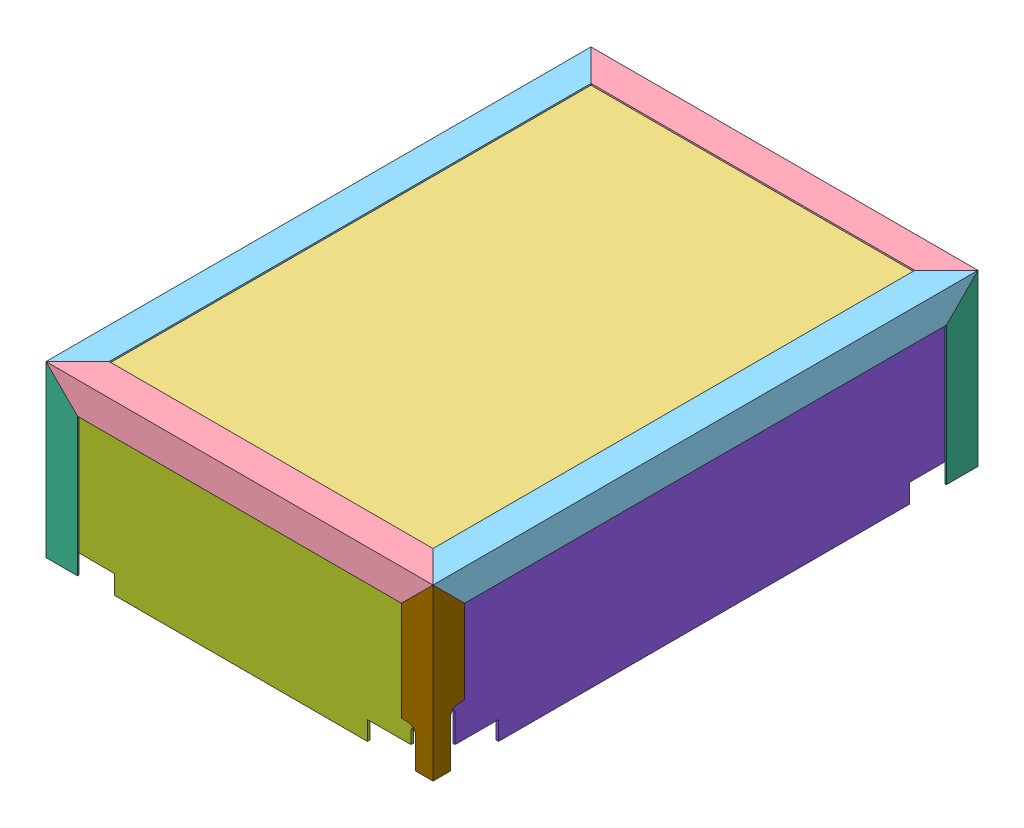
SolidWorks assembly couvercle, configuration Défaut. Lengths in mm.
Overall size (490 215 690).
13 component instances, 9 part files, 32 mates.
Components (placement in the parent):
- plaque_acrylique_680x210-2: plaque_acrylique_680x210 [Défaut] at (-694.8689 73.91 -173.3892) x (0 0 -1) z (1 0 0) size (680 210 3)
- plaque_acrylique_380x210-2: plaque_acrylique_380x210 [Défaut] at (-401.8689 73.91 -516.3892) size (480 210 3)
- plaque_acrylique_380x680-1: plaque_acrylique_380x680 [Défaut] at (-401.8689 178.91 -173.3892) x (1 0 0) z (0 1 0) size (480 680 3)
- eclisse_40x40x404_bisote_x2-1: eclisse_40x40x404_bisote_x2 [Défaut] at (-206.8689 163.7964 -498.3892) x (0 0 1) z (0 -1 0) size (40 490 40)
- eclisse_40x40x704_bisote_x2-1: eclisse_40x40x704_bisote_x2 [Défaut] at (-226.9825 163.91 -518.3892) x (0 -1 0) z (-1 0 0) size (40 690 40)
- eclisse_40x40x404_bisote_x2-2: eclisse_40x40x404_bisote_x2 [Défaut] at (-696.8689 163.7964 151.6108) x (0 0 -1) z (0 -1 0) size (40 490 40)
- eclisse_40x40x704_bisote_x2-2: eclisse_40x40x704_bisote_x2 [Défaut] at (-676.8689 163.7964 -518.3892) x (1 0 0) z (0 -1 0) size (40 690 40)
- eclisse_40x40x222_bisote_x1-1: eclisse_40x40x222_bisote_x1 [Défaut] at (-676.7552 183.91 -498.3892) x (0 0 1) z (1 0 0) size (40 213 40)
- eclisse_40x40x222_bisote_x1-2: eclisse_40x40x222_bisote_x1 [Défaut] at (-226.8689 183.91 -498.2755) x (-1 0 0) z (0 0 1) size (40 213 40)
- eclisse_40x40x222_bisote_x1-4: eclisse_40x40x222_bisote_x1 [Défaut] at (-676.8689 183.91 151.4972) x (1 0 0) z (0 0 -1) size (40 213 40)
- plaque_acrylique_380x210_Moteur-1: plaque_acrylique_380x210_Moteur [Défaut] at (-401.8689 73.91 166.6108) size (480 210 3)
- plaque_acrylique_680x210_moteur-1: plaque_acrylique_680x210_moteur [Défaut] at (-211.8689 73.91 -173.3892) x (0 0 -1) z (1 0 0) size (680 210 3)
- eclisse_40x40x222_bisote_x1_Moteur-1: eclisse_40x40x222_bisote_x1_Moteur [Défaut] at (-226.9825 183.91 151.6108) x (0 0 -1) z (-1 0 0) size (40 213 40)
Mates (geometry in assembly coordinates):
- Coïncidente1: coincident anti-aligned: plane of plaque_acrylique_380x680-1 through (-401.8689 181.91 -173.3892) normal (0 1 0); plane of eclisse_40x40x704_bisote_x2-1 through (-208.8689 181.91 171.6108) normal (0 -1 0)
- Coïncidente2: coincident anti-aligned: plane of eclisse_40x40x704_bisote_x2-1 through (-208.8689 181.91 171.6108) normal (-1 0 0); plane of plaque_acrylique_680x210_moteur-1 through (-208.8689 73.91 -173.3892) normal (1 0 0)
- Coïncidente3: coincident anti-aligned: plane of plaque_acrylique_380x210-2 through (-401.8689 73.91 -516.3892) normal (0 0 -1); plane of eclisse_40x40x404_bisote_x2-1 through (-696.8689 181.91 -516.3892) normal (0 0 1)
- Coïncidente4: coincident anti-aligned: plane of plaque_acrylique_380x680-1 through (-401.8689 181.91 -173.3892) normal (0 1 0); plane of eclisse_40x40x404_bisote_x2-1 through (-696.8689 181.91 -516.3892) normal (0 -1 0)
- Coïncidente5: coincident anti-aligned: plane of plaque_acrylique_680x210-2 through (-694.8689 73.91 -173.3892) normal (-1 0 0); plane of eclisse_40x40x704_bisote_x2-2 through (-694.8689 181.91 171.6108) normal (1 0 0)
- Coïncidente6: coincident anti-aligned: plane of plaque_acrylique_380x680-1 through (-401.8689 181.91 -173.3892) normal (0 1 0); plane of eclisse_40x40x704_bisote_x2-2 through (-694.8689 181.91 171.6108) normal (0 -1 0)
- Coïncidente7: coincident anti-aligned: plane of eclisse_40x40x404_bisote_x2-2 through (-206.8689 181.91 169.6108) normal (0 0 -1); plane of plaque_acrylique_380x210_Moteur-1 through (-401.8689 73.91 169.6108) normal (0 0 1)
- Coïncidente9: coincident anti-aligned: plane of plaque_acrylique_380x210_Moteur-1 through (-401.8689 73.91 169.6108) normal (0 0 1); plane of eclisse_40x40x222_bisote_x1_Moteur-1 through (-208.8689 -31.09 169.6108) normal (0 0 -1)
- Coïncidente10: coincident anti-aligned: plane of plaque_acrylique_680x210_moteur-1 through (-208.8689 73.91 -173.3892) normal (1 0 0); plane of eclisse_40x40x222_bisote_x1_Moteur-1 through (-208.8689 -31.09 169.6108) normal (-1 0 0)
- Coïncidente11: coincident anti-aligned: plane of plaque_acrylique_380x210-2 through (-401.8689 73.91 -516.3892) normal (0 0 -1); plane of eclisse_40x40x222_bisote_x1-2 through (-208.8689 -31.09 -516.3892) normal (0 0 1)
- Coïncidente12: coincident anti-aligned: plane of eclisse_40x40x222_bisote_x1-2 through (-208.8689 -31.09 -516.3892) normal (-1 0 0); plane of plaque_acrylique_680x210_moteur-1 through (-208.8689 73.91 -173.3892) normal (1 0 0)
- Coïncidente13: coincident anti-aligned: plane of plaque_acrylique_680x210-2 through (-694.8689 73.91 -173.3892) normal (-1 0 0); plane of eclisse_40x40x222_bisote_x1-1 through (-694.8689 -31.09 -516.3892) normal (1 0 0)
- Coïncidente14: coincident anti-aligned: plane of plaque_acrylique_380x210-2 through (-401.8689 73.91 -516.3892) normal (0 0 -1); plane of eclisse_40x40x222_bisote_x1-1 through (-694.8689 -31.09 -516.3892) normal (0 0 1)
- Coïncidente15: coincident anti-aligned: plane of eclisse_40x40x222_bisote_x1-4 through (-694.8689 -31.09 169.6108) normal (0 0 -1); plane of plaque_acrylique_380x210_Moteur-1 through (-401.8689 73.91 169.6108) normal (0 0 1)
- Coïncidente16: coincident anti-aligned: plane of plaque_acrylique_680x210-2 through (-694.8689 73.91 -173.3892) normal (-1 0 0); plane of eclisse_40x40x222_bisote_x1-4 through (-694.8689 -31.09 169.6108) normal (1 0 0)
- Coïncidente19: coincident anti-aligned: line of plaque_acrylique_380x210_Moteur-1 through (-211.8689 -7.09 166.6108) axis (0 1 0); line of plaque_acrylique_680x210_moteur-1 through (-211.8689 178.91 166.6108) axis (0 -1 0)
- Coïncidente20: coincident aligned: plane of plaque_acrylique_380x210_Moteur-1 through (-211.8689 -7.09 166.6108) normal (0 -1 0); plane of plaque_acrylique_680x210_moteur-1 through (-211.8689 -7.09 166.6108) normal (0 -1 0)
- Coïncidente21: coincident aligned: line of plaque_acrylique_680x210-2 through (-691.8689 178.91 166.6108) axis (0 -1 0); line of plaque_acrylique_380x210_Moteur-1 through (-691.8689 178.91 166.6108) axis (0 -1 0)
- Coïncidente22: coincident aligned: plane of plaque_acrylique_680x210-2 through (-694.8689 -7.09 166.6108) normal (0 -1 0); plane of plaque_acrylique_380x210_Moteur-1 through (-691.8689 -7.09 166.6108) normal (0 -1 0)
- Coïncidente23: coincident anti-aligned: line of plaque_acrylique_680x210-2 through (-691.8689 -7.09 -513.3892) axis (0 1 0); line of plaque_acrylique_380x210-2 through (-691.8689 178.91 -513.3892) axis (0 -1 0)
- Coïncidente24: coincident aligned: plane of plaque_acrylique_680x210-2 through (-694.8689 -7.09 -513.3892) normal (0 -1 0); plane of plaque_acrylique_380x210-2 through (-691.8689 -7.09 -516.3892) normal (0 -1 0)
- Coïncidente28: coincident anti-aligned: line of plaque_acrylique_380x680-1 through (-691.8689 178.91 166.6108) axis (1 0 0); line of plaque_acrylique_380x210_Moteur-1 through (-211.8689 178.91 166.6108) axis (-1 0 0)
- Coïncidente29: coincident aligned: line of plaque_acrylique_680x210-2 through (-691.8689 178.91 -513.3892) axis (0 0 1); line of plaque_acrylique_380x680-1 through (-691.8689 178.91 -513.3892) axis (0 0 1)
- Coïncidente30: coincident anti-aligned: plane of plaque_acrylique_380x680-1 through (-401.8689 181.91 -173.3892) normal (0 1 0); plane of eclisse_40x40x404_bisote_x2-2 through (-206.8689 181.91 169.6108) normal (0 -1 0)
- Coïncidente31: coincident anti-aligned: line of eclisse_40x40x404_bisote_x2-2 through (-206.8689 183.91 171.6108) axis (-0.707107 -0.707107 0); line of eclisse_40x40x222_bisote_x1_Moteur-1 through (-246.8689 143.91 171.6108) axis (0.707107 0.707107 0)
- Coïncidente32: coincident anti-aligned: line of eclisse_40x40x704_bisote_x2-1 through (-206.8689 143.91 131.6108) axis (0 0.707107 0.707107); line of eclisse_40x40x222_bisote_x1_Moteur-1 through (-206.8689 183.91 171.6108) axis (0 -0.707107 -0.707107)
- Coïncidente35: coincident anti-aligned: line of eclisse_40x40x404_bisote_x2-2 through (-656.8689 143.91 171.6108) axis (-0.707107 0.707107 0); line of eclisse_40x40x222_bisote_x1-4 through (-696.8689 183.91 171.6108) axis (0.707107 -0.707107 0)
- Coïncidente36: coincident anti-aligned: line of eclisse_40x40x704_bisote_x2-2 through (-696.8689 183.91 171.6108) axis (0 -0.707107 -0.707107); line of eclisse_40x40x222_bisote_x1-4 through (-696.8689 143.91 131.6108) axis (0 0.707107 0.707107)
- Coïncidente37: coincident anti-aligned: line of eclisse_40x40x404_bisote_x2-2 through (-696.8689 183.91 171.6108) axis (0.707107 0 -0.707107); line of eclisse_40x40x704_bisote_x2-2 through (-656.8689 183.91 131.6108) axis (-0.707107 0 0.707107)
- Coïncidente38: coincident anti-aligned: line of eclisse_40x40x404_bisote_x2-1 through (-656.8689 183.91 -478.3892) axis (-0.707107 0 -0.707107); line of eclisse_40x40x704_bisote_x2-2 through (-696.8689 183.91 -518.3892) axis (0.707107 0 0.707107)
- Coïncidente39: coincident anti-aligned: line of eclisse_40x40x704_bisote_x2-2 through (-696.8689 143.91 -478.3892) axis (0 0.707107 -0.707107); line of eclisse_40x40x222_bisote_x1-1 through (-696.8689 183.91 -518.3892) axis (0 -0.707107 0.707107)
- Coïncidente40: coincident anti-aligned: line of eclisse_40x40x404_bisote_x2-1 through (-246.8689 143.91 -518.3892) axis (0.707107 0.707107 0); line of eclisse_40x40x222_bisote_x1-2 through (-206.8689 183.91 -518.3892) axis (-0.707107 -0.707107 0)
